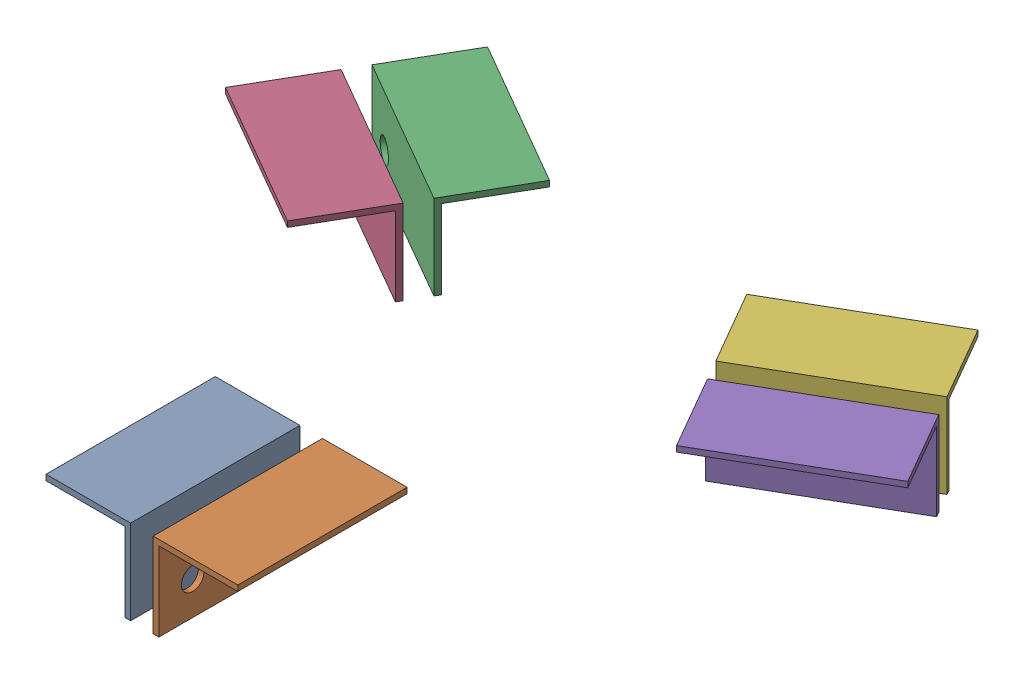
SolidWorks assembly СтанинаСб, configuration По умолчанию. Lengths in mm.
Overall size (604.62 75 523.61).
9 component instances, 2 part files, 2 mates.
Components (placement in the parent):
- ПроушинаСб-1: ПроушинаСб [По умолчанию] at (0 0 300) x (-1 0 0) z (0 0 1) size (170 75 150)
  - ПроушинаЛ-1: ПроушинаЛ [По умолчанию] at (10 0 -150) x (1 0 0) z (0 -1 0) size (75 150 75)
  - ПроушинаП-1: ПроушинаП [По умолчанию] at (-10 0 -150) x (0 1 0) z (1 0 0) size (75 150 75)
- ПроушинаСб-4: ПроушинаСб [По умолчанию] at (-259.8076 0 -150) x (0.5 0 -0.866025) z (-0.866025 0 -0.5) size (170 75 150)
  - ПроушинаЛ-1: ПроушинаЛ [По умолчанию] at (10 0 -150) x (1 0 0) z (0 -1 0) size (75 150 75)
  - ПроушинаП-1: ПроушинаП [По умолчанию] at (-10 0 -150) x (0 1 0) z (1 0 0) size (75 150 75)
- ПроушинаСб-5: ПроушинаСб [По умолчанию] at (259.8076 0 -150) x (0.5 0 0.866025) z (0.866025 0 -0.5) size (170 75 150)
  - ПроушинаЛ-1: ПроушинаЛ [По умолчанию] at (10 0 -150) x (1 0 0) z (0 -1 0) size (75 150 75)
  - ПроушинаП-1: ПроушинаП [По умолчанию] at (-10 0 -150) x (0 1 0) z (1 0 0) size (75 150 75)
Mates (geometry in assembly coordinates):
- Совпадение2: coincident anti-aligned: plane of ПроушинаСб-1 through (0 0 300) normal (-1 0 0)
- Расстояние1: distance = 150 mm anti-aligned: plane of ПроушинаСб-1/ПроушинаЛ-1 through (-10 0 150) normal (0 0 -1)
